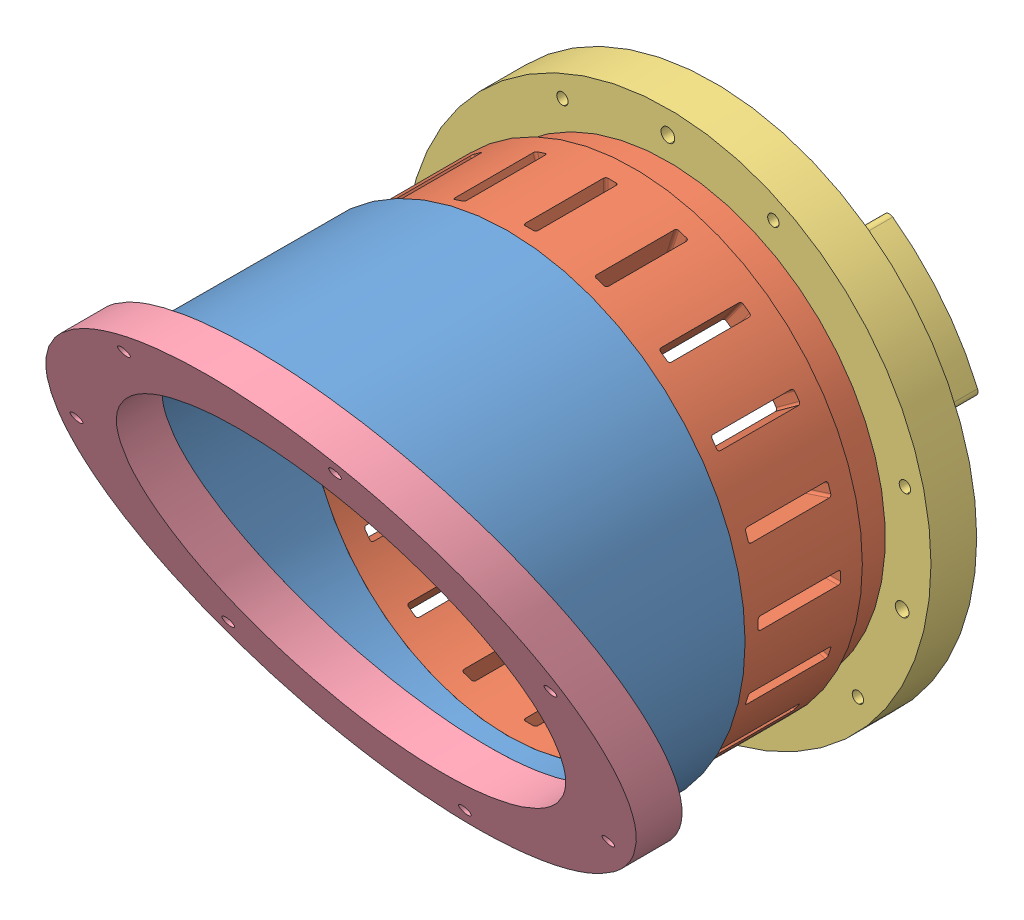
SolidWorks assembly L.Z.D V2.1, configuration Défaut. Lengths in mm.
Overall size (46 46 46.89).
4 component instances, 4 part files, 12 mates.
Components (placement in the parent):
- Lentille - Tube - C Attaque-1: Lentille - Tube - C Attaque [Défaut] at (-6.3772 -2.6108 34.1949) x (-1 0 0) z (0 0 1) size (41.5 41.5 21.15)
- Lentille - Tube Attaque-1: Lentille - Tube Attaque [Défaut] at (-6.3772 -2.6108 52.1949) x (-1 0 0) z (0 0 -1) size (40 40 14)
- Lentille - Rondelle N°2 V3-1: Lentille - Rondelle N°2 V3 [Défaut] at (-6.3772 -2.6108 16.1949) x (-1 0 0) z (0 0 1) size (46 46 6.6)
- Lentille - Rondelle N°1 Attaque-2: Lentille - Rondelle N°1 Attaque [Défaut] at (-6.3772 -2.6108 73.0485) x (1 0 0) z (0 0 -1) size (46 46 27.44)
Mates (geometry in assembly coordinates):
- Coïncidente1: coincident: plane of ? through (-28.7484 25.144 55.7191) normal (0 0.45399 -0.891007); plane of ? through (15.0016 -18.606 33.4273) normal (0 -0.45399 0.891007)
- Coaxiale1: concentric: cylinder of ? through (-5.7484 2.144 59.7191) axis (0 0 -1) radius 17.5; cylinder of ? through (-5.7484 2.144 80.4273) axis (0 0 -1) radius 17.5
- Parallèle1: parallel: plane of assembly through (0 0 0) normal (0 0 1); plane of Lentille - Tube - C Attaque-1 through (-6.3772 -2.6108 34.1949) normal (0 0 -1); plane of assembly
- Parallèle2: parallel: plane of ? through (-5.7484 2.144 19.7191) normal (1 0 0); plane of assembly through (0 0 0) normal (1 0 0)
- Coïncidente2: coincident: plane of assembly; plane of assembly; plane of Lentille - Tube - C Attaque-1 through (-6.3772 -2.6108 34.1949) normal (0 0 -1); plane of Lentille - Tube Attaque-1 through (-6.3772 -22.6108 34.1949) normal (0 0 1)
- Coaxiale2: concentric: cylinder of assembly; cylinder of assembly; cylinder of Lentille - Tube - C Attaque-1 through (-6.3772 -2.6108 81.1949) axis (0 0 -1) radius 17.5; cylinder of Lentille - Tube Attaque-1 through (-6.3772 -2.6108 15.1949) axis (0 0 1) radius 17.5
- Coïncidente3: coincident: line of ?; line of ? through (-5.7484 22.144 31.5361) axis (0 0 -1)
- Coïncidente4: coincident: plane of assembly; plane of assembly; plane of Lentille - Tube Attaque-1 through (-6.3772 -2.6108 20.1949) normal (0 0 -1); plane of Lentille - Rondelle N°2 V3-1 through (-6.3772 -2.6108 20.1949) normal (0 0 1)
- Coaxiale3: concentric: cylinder of assembly; cylinder of assembly; cylinder of Lentille - Tube Attaque-1 through (-6.3772 -2.6108 15.1949) axis (0 0 1) radius 17.5; cylinder of Lentille - Rondelle N°2 V3-1 through (-6.3772 -2.6108 20.1949) axis (0 0 -1) radius 17.5
- Coïncidente5: coincident: plane of assembly; plane of assembly; plane of Lentille - Tube - C Attaque-1 through (14.3728 -23.3608 34.1949) normal (0 -0.45399 0.891007); plane of Lentille - Rondelle N°1 Attaque-2 through (-29.3772 20.3892 56.4866) normal (0 0.45399 -0.891007)
- Coaxiale4: concentric: cylinder of assembly; cylinder of assembly; cylinder of Lentille - Tube - C Attaque-1 through (-6.3772 -2.6108 81.1949) axis (0 0 -1) radius 17.5; cylinder of Lentille - Rondelle N°1 Attaque-2 through (-6.3772 -2.6108 33.0485) axis (0 0 1) radius 17.5
- Coaxiale5: concentric: cylinder of assembly; cylinder of assembly; cylinder of Lentille - Rondelle N°2 V3-1 through (-6.3772 -23.8608 20.1949) axis (0 0 -1) radius 0.5; cylinder of Lentille - Rondelle N°1 Attaque-2 through (-6.3772 -23.8608 33.0485) axis (0 0 1) radius 0.5
